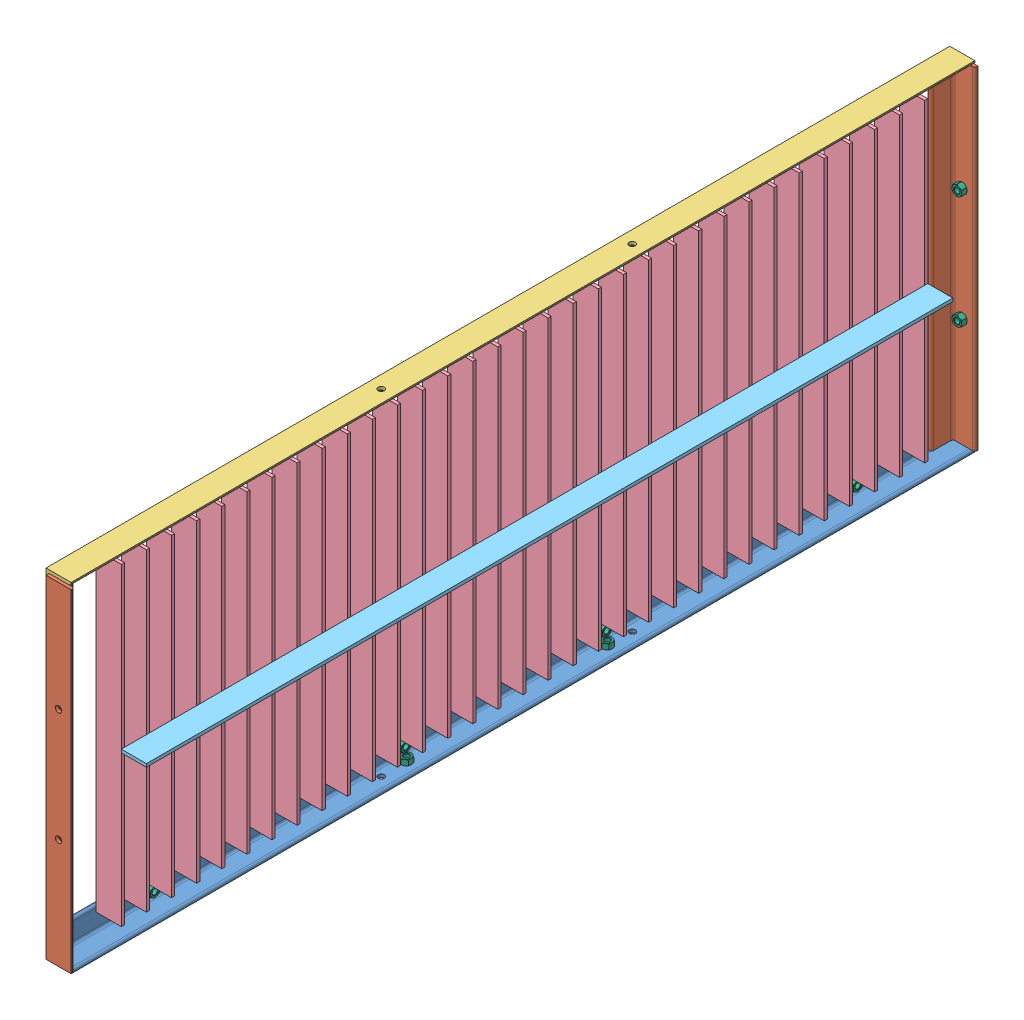
SolidWorks assembly 01-070-00-0, configuration Default. Lengths in mm.
Overall size (107.95 685.8 1835.15).
50 component instances, 6 part files, 45 mates.
Components (placement in the parent):
- 01-068-00-0-4: 01-068-00-0 [Default] at origin size (50.8 50.8 1828.8)
- 01-069-00-0-1: 01-069-00-0 [Default] at (6.35 342.9 920.75) x (1 0 0) z (0 1 0) size (50.8 50.8 673.1)
- 01-069-00-0-5: 01-069-00-0 [Default] at (6.35 342.9 -914.4) x (1 0 0) z (0 -1 0) size (50.8 50.8 673.1)
- 01-086-00-0-3: 01-086-00-0 [Default] at (0 685.8 0) x (1 0 0) z (0 0 -1) size (50.8 50.8 1828.8)
- 01-071-00-0-1: 01-071-00-0 [Default] at (6.35 355.6 812.8) size (50.8 635 6.35)
- 01-071-00-0-2: 01-071-00-0 [Default] at (6.35 355.6 762) size (50.8 635 6.35)
- 01-071-00-0-3: 01-071-00-0 [Default] at (6.35 355.6 711.2) size (50.8 635 6.35)
- 01-071-00-0-4: 01-071-00-0 [Default] at (6.35 355.6 660.4) size (50.8 635 6.35)
- 01-071-00-0-5: 01-071-00-0 [Default] at (6.35 355.6 609.6) size (50.8 635 6.35)
- 01-071-00-0-6: 01-071-00-0 [Default] at (6.35 355.6 558.8) size (50.8 635 6.35)
- 01-071-00-0-7: 01-071-00-0 [Default] at (6.35 355.6 508) size (50.8 635 6.35)
- 01-071-00-0-8: 01-071-00-0 [Default] at (6.35 355.6 457.2) size (50.8 635 6.35)
- 01-071-00-0-9: 01-071-00-0 [Default] at (6.35 355.6 406.4) size (50.8 635 6.35)
- 01-071-00-0-10: 01-071-00-0 [Default] at (6.35 355.6 355.6) size (50.8 635 6.35)
- 01-071-00-0-11: 01-071-00-0 [Default] at (6.35 355.6 304.8) size (50.8 635 6.35)
- 01-071-00-0-12: 01-071-00-0 [Default] at (6.35 355.6 254) size (50.8 635 6.35)
- 01-071-00-0-13: 01-071-00-0 [Default] at (6.35 355.6 203.2) size (50.8 635 6.35)
- 01-071-00-0-14: 01-071-00-0 [Default] at (6.35 355.6 152.4) size (50.8 635 6.35)
- 01-071-00-0-15: 01-071-00-0 [Default] at (6.35 355.6 101.6) size (50.8 635 6.35)
- 01-071-00-0-16: 01-071-00-0 [Default] at (6.35 355.6 50.8) size (50.8 635 6.35)
- 01-071-00-0-17: 01-071-00-0 [Default] at (6.35 355.6 0) size (50.8 635 6.35)
- 01-071-00-0-18: 01-071-00-0 [Default] at (6.35 355.6 -50.8) size (50.8 635 6.35)
- 01-071-00-0-19: 01-071-00-0 [Default] at (6.35 355.6 -101.6) size (50.8 635 6.35)
- 01-071-00-0-20: 01-071-00-0 [Default] at (6.35 355.6 -152.4) size (50.8 635 6.35)
- 01-071-00-0-21: 01-071-00-0 [Default] at (6.35 355.6 -203.2) size (50.8 635 6.35)
- 01-071-00-0-22: 01-071-00-0 [Default] at (6.35 355.6 -254) size (50.8 635 6.35)
- 01-071-00-0-23: 01-071-00-0 [Default] at (6.35 355.6 -304.8) size (50.8 635 6.35)
- 01-071-00-0-24: 01-071-00-0 [Default] at (6.35 355.6 -355.6) size (50.8 635 6.35)
- 01-071-00-0-25: 01-071-00-0 [Default] at (6.35 355.6 -406.4) size (50.8 635 6.35)
- 01-071-00-0-26: 01-071-00-0 [Default] at (6.35 355.6 -457.2) size (50.8 635 6.35)
- 01-071-00-0-27: 01-071-00-0 [Default] at (6.35 355.6 -508) size (50.8 635 6.35)
- 01-071-00-0-28: 01-071-00-0 [Default] at (6.35 355.6 -558.8) size (50.8 635 6.35)
- 01-071-00-0-29: 01-071-00-0 [Default] at (6.35 355.6 -609.6) size (50.8 635 6.35)
- 01-071-00-0-30: 01-071-00-0 [Default] at (6.35 355.6 -660.4) size (50.8 635 6.35)
- 01-071-00-0-31: 01-071-00-0 [Default] at (6.35 355.6 -711.2) size (50.8 635 6.35)
- 01-071-00-0-32: 01-071-00-0 [Default] at (6.35 355.6 -762) size (50.8 635 6.35)
- 01-071-00-0-33: 01-071-00-0 [Default] at (6.35 355.6 -812.8) size (50.8 635 6.35)
- 01-118-00-0-1: 01-118-00-0 [Default] at (57.15 342.9 -812.8) x (0 0 1) z (-1 0 0) size (1631.95 6.35 50.8)
- hex nut_ai-4: hex nut_ai [HNUT 0.5000-13-D-C] at (25.4 17.7292 210.566) x (1 0 0) z (0 1 0) size (19.05 22 11.38)
- hex nut_ai-5: hex nut_ai [HNUT 0.5000-13-D-C] at (25.4 17.7292 -195.834) x (1 0 0) z (0 1 0) size (19.05 22 11.38)
- hex nut_ai-6: hex nut_ai [HNUT 0.5000-13-D-C] at (17.7292 25.4 711.2) x (0 0 -1) z (1 0 0) size (19.05 22 11.38)
- hex nut_ai-7: hex nut_ai [HNUT 0.5000-13-D-C] at (17.7292 25.4 203.2) x (0 0 -1) z (1 0 0) size (19.05 22 11.38)
- hex nut_ai-8: hex nut_ai [HNUT 0.5000-13-D-C] at (17.7292 25.4 -203.2) x (0 0 -1) z (1 0 0) size (19.05 22 11.38)
- hex nut_ai-9: hex nut_ai [HNUT 0.5000-13-D-C] at (17.7292 25.4 -711.2) x (0 0 -1) z (1 0 0) size (19.05 22 11.38)
- hex nut_ai-10: hex nut_ai [HNUT 0.5000-13-D-C] at (25.4 668.0708 -246.634) x (1 0 0) z (0 -1 0) size (19.05 22 11.38)
- hex nut_ai-11: hex nut_ai [HNUT 0.5000-13-D-C] at (25.4 668.0708 261.366) x (1 0 0) z (0 -1 0) size (19.05 22 11.38)
- hex nut_ai-12: hex nut_ai [HNUT 0.5000-13-D-C] at (31.75 457.2 -896.6708) size (19.05 22 11.38)
- hex nut_ai-13: hex nut_ai [HNUT 0.5000-13-D-C] at (31.75 228.6 -896.6708) size (19.05 22 11.38)
- hex nut_ai-14: hex nut_ai [HNUT 0.5000-13-D-C] at (31.75 457.2 903.0208) x (0.923728 0.383049 0) z (0 0 -1) size (19.05 22 11.38)
- hex nut_ai-15: hex nut_ai [HNUT 0.5000-13-D-C] at (31.75 228.6 903.0208) x (0.923728 0.383049 0) z (0 0 -1) size (19.05 22 11.38)
Mates (geometry in assembly coordinates):
- Coincident19: coincident aligned: plane of 01-068-00-0-4 through (0 0 0) normal (0 0 1); plane of assembly through (0 0 0) normal (0 0 1)
- Coincident20: coincident aligned: plane of 01-068-00-0-4 through (0 0 0) normal (1 0 0); plane of assembly through (0 0 0) normal (1 0 0)
- Coincident21: coincident aligned: plane of 01-068-00-0-4 through (0 0 0) normal (0 1 0); plane of assembly through (0 0 0) normal (0 1 0)
- Tangent1: tangent: plane of 01-068-00-0-4 through (6.35 46.0426 914.4) normal (1 0 0); cylinder of 01-071-00-0-1 through (12.7 901.7 812.8) axis (0 -1 0) radius 6.35
- Distance1: distance = 31.75 mm anti-aligned: plane of 01-071-00-0-1 through (6.35 38.1 819.15) normal (0 -1 0); plane of 01-068-00-0-4 through (11.1125 6.35 914.4) normal (0 1 0)
- Distance2: distance = 44.45 mm: plane of 01-069-00-0-1 through (6.35 908.05 863.6) normal (0 0 -1); cylinder of 01-071-00-0-1 through (12.7 901.7 812.8) axis (0 -1 0) radius 6.35
- Coincident35: coincident anti-aligned: plane of 01-068-00-0-4 through (6.35 46.0426 914.4) normal (1 0 0); plane of 01-069-00-0-5 through (6.35 6.35 -914.4) normal (-1 0 0)
- Coincident36: coincident aligned: plane of 01-068-00-0-4 through (1.5926 46.0426 -914.4) normal (0 0 -1); plane of 01-069-00-0-5 through (57.15 6.35 -914.4) normal (0 0 -1)
- Coincident37: coincident anti-aligned: plane of 01-068-00-0-4 through (11.1125 6.35 914.4) normal (0 1 0); plane of 01-069-00-0-5 through (7.9426 6.35 -868.3574) normal (0 -1 0)
- Coincident38: coincident anti-aligned: plane of 01-068-00-0-4 through (6.35 46.0426 914.4) normal (1 0 0); plane of 01-069-00-0-1 through (6.35 679.45 920.75) normal (-1 0 0)
- Coincident39: coincident anti-aligned: plane of 01-068-00-0-4 through (11.1125 6.35 914.4) normal (0 1 0); plane of 01-069-00-0-1 through (7.9426 6.35 874.7074) normal (0 -1 0)
- Coincident41: coincident anti-aligned: plane of 01-069-00-0-1 through (7.9426 679.45 874.7074) normal (0 1 0); plane of 01-086-00-0-3 through (11.1125 679.45 -914.4) normal (0 -1 0)
- Coincident43: coincident aligned: plane of 01-068-00-0-4 through (0 0 914.4) normal (-1 0 0); plane of 01-086-00-0-3 through (0 685.8 -914.4) normal (-1 0 0)
- Coincident44: coincident aligned: plane of 01-068-00-0-4 through (1.5926 46.0426 914.4) normal (0 0 1); plane of 01-086-00-0-3 through (1.5926 639.7574 914.4) normal (0 0 1)
- Distance4: distance = 101.6 mm: moEndPointRef_w of 01-071-00-0-1; plane of 01-086-00-0-3 through (1.5926 868.3574 914.4) normal (0 0 1)
- Distance6: distance = 342.9 mm aligned: plane of 01-118-00-0-1 through (107.95 342.9 -812.8) normal (0 -1 0); plane of 01-068-00-0-4 through (50.8 0 914.4) normal (0 -1 0)
- Coincident53: coincident anti-aligned: plane of 01-071-00-0-33 through (57.15 673.1 -812.8) normal (1 0 0); plane of 01-118-00-0-1 through (57.15 349.25 -812.8) normal (-1 0 0)
- Coincident54: coincident aligned: plane of 01-071-00-0-33 through (6.35 673.1 -812.8) normal (0 0 -1); plane of 01-118-00-0-1 through (57.15 349.25 -812.8) normal (0 0 -1)
- Coincident55: coincident anti-aligned: plane of 01-068-00-0-4 through (1.5926 46.0426 914.4) normal (0 0 1); plane of 01-069-00-0-1 through (17.4625 679.45 914.4) normal (0 0 -1)
- Coincident56: coincident anti-aligned: plane of 01-086-00-0-3 through (6.35 639.7574 -914.4) normal (1 0 0); plane of 01-071-00-0-1 through (6.35 673.1 812.8) normal (-1 0 0)
- Coincident57: coincident anti-aligned: plane of 01-071-00-0-33 through (57.15 673.1 -812.8) normal (1 0 0); plane of 01-118-00-0-1 through (57.15 349.25 -812.8) normal (-1 0 0)
- Concentric21: concentric anti-aligned: cylinder of 01-068-00-0-4 through (25.4 0 210.566) axis (0 -1 0) radius 6.35; cylinder of hex nut_ai-4 through (25.4 -7.3083 210.566) axis (0 1 0) radius 6.35
- Coincident591: coincident anti-aligned: plane of 01-068-00-0-4 through (11.1125 6.35 914.4) normal (0 1 0); plane of hex nut_ai-4 through (25.4 6.35 199.5675) normal (0 -1 0)
- Concentric31: concentric anti-aligned: cylinder of 01-068-00-0-4 through (25.4 0 -195.834) axis (0 -1 0) radius 6.35; cylinder of hex nut_ai-5 through (25.4 -7.3083 -195.834) axis (0 1 0) radius 6.35
- Coincident601: coincident anti-aligned: plane of 01-068-00-0-4 through (11.1125 6.35 914.4) normal (0 1 0); plane of hex nut_ai-5 through (25.4 6.35 -206.8325) normal (0 -1 0)
- Concentric41: concentric anti-aligned: cylinder of 01-068-00-0-4 through (0 25.4 711.2) axis (-1 0 0) radius 7.9375; cylinder of hex nut_ai-6 through (-7.3083 25.4 711.2) axis (1 0 0) radius 6.35
- Coincident611: coincident anti-aligned: plane of 01-068-00-0-4 through (6.35 46.0426 914.4) normal (1 0 0); plane of hex nut_ai-6 through (6.35 36.3985 711.2) normal (-1 0 0)
- Concentric51: concentric anti-aligned: cylinder of 01-068-00-0-4 through (0 25.4 203.2) axis (-1 0 0) radius 7.9375; cylinder of hex nut_ai-7 through (-7.3083 25.4 203.2) axis (1 0 0) radius 6.35
- Coincident621: coincident anti-aligned: plane of 01-068-00-0-4 through (6.35 46.0426 914.4) normal (1 0 0); plane of hex nut_ai-7 through (6.35 36.3985 203.2) normal (-1 0 0)
- Concentric61: concentric anti-aligned: cylinder of 01-068-00-0-4 through (0 25.4 -203.2) axis (-1 0 0) radius 7.9375; cylinder of hex nut_ai-8 through (-7.3083 25.4 -203.2) axis (1 0 0) radius 6.35
- Coincident631: coincident anti-aligned: plane of 01-068-00-0-4 through (6.35 46.0426 914.4) normal (1 0 0); plane of hex nut_ai-8 through (6.35 36.3985 -203.2) normal (-1 0 0)
- Concentric71: concentric anti-aligned: cylinder of 01-068-00-0-4 through (0 25.4 -711.2) axis (-1 0 0) radius 7.9375; cylinder of hex nut_ai-9 through (-7.3083 25.4 -711.2) axis (1 0 0) radius 6.35
- Coincident641: coincident anti-aligned: plane of 01-068-00-0-4 through (6.35 46.0426 914.4) normal (1 0 0); plane of hex nut_ai-9 through (6.35 36.3985 -711.2) normal (-1 0 0)
- Concentric81: concentric anti-aligned: cylinder of 01-086-00-0-3 through (25.4 634.999 -246.634) axis (0 1 0) radius 6.35; cylinder of hex nut_ai-10 through (25.4 693.1083 -246.634) axis (0 -1 0) radius 6.35
- Coincident651: coincident anti-aligned: plane of 01-086-00-0-3 through (11.1125 679.45 -914.4) normal (0 -1 0); plane of hex nut_ai-10 through (25.4 679.45 -235.6355) normal (0 1 0)
- Concentric91: concentric anti-aligned: cylinder of 01-086-00-0-3 through (25.4 634.999 261.366) axis (0 1 0) radius 6.35; cylinder of hex nut_ai-11 through (25.4 693.1083 261.366) axis (0 -1 0) radius 6.35
- Coincident661: coincident anti-aligned: plane of 01-086-00-0-3 through (11.1125 679.45 -914.4) normal (0 -1 0); plane of hex nut_ai-11 through (25.4 679.45 272.3645) normal (0 1 0)
- Concentric921: concentric anti-aligned: cylinder of 01-069-00-0-5 through (31.75 457.2 -863.6) axis (0 0 -1) radius 6.35; cylinder of hex nut_ai-12 through (31.75 457.2 -921.7083) axis (0 0 1) radius 6.35
- Coincident6621: coincident anti-aligned: plane of 01-069-00-0-5 through (17.4625 6.35 -908.05) normal (0 0 1); plane of hex nut_ai-12 through (31.75 468.1985 -908.05) normal (0 0 -1)
- Concentric931: concentric anti-aligned: cylinder of 01-069-00-0-5 through (31.75 228.6 -863.6) axis (0 0 -1) radius 6.35; cylinder of hex nut_ai-13 through (31.75 228.6 -921.7083) axis (0 0 1) radius 6.35
- Coincident6631: coincident anti-aligned: plane of 01-069-00-0-5 through (17.4625 6.35 -908.05) normal (0 0 1); plane of hex nut_ai-13 through (31.75 239.5985 -908.05) normal (0 0 -1)
- Concentric941: concentric anti-aligned: cylinder of 01-069-00-0-1 through (31.75 457.2 869.95) axis (0 0 1) radius 6.35; cylinder of hex nut_ai-14 through (31.75 457.2 928.0583) axis (0 0 -1) radius 6.35
- Coincident6641: coincident anti-aligned: plane of 01-069-00-0-1 through (17.4625 679.45 914.4) normal (0 0 -1); plane of hex nut_ai-14 through (35.963 447.0404 914.4) normal (0 0 1)
- Concentric951: concentric anti-aligned: cylinder of 01-069-00-0-1 through (31.75 228.6 869.95) axis (0 0 1) radius 6.35; cylinder of hex nut_ai-15 through (31.75 228.6 928.0583) axis (0 0 -1) radius 6.35
- Coincident6651: coincident anti-aligned: plane of 01-069-00-0-1 through (17.4625 679.45 914.4) normal (0 0 -1); plane of hex nut_ai-15 through (35.963 218.4404 914.4) normal (0 0 1)
